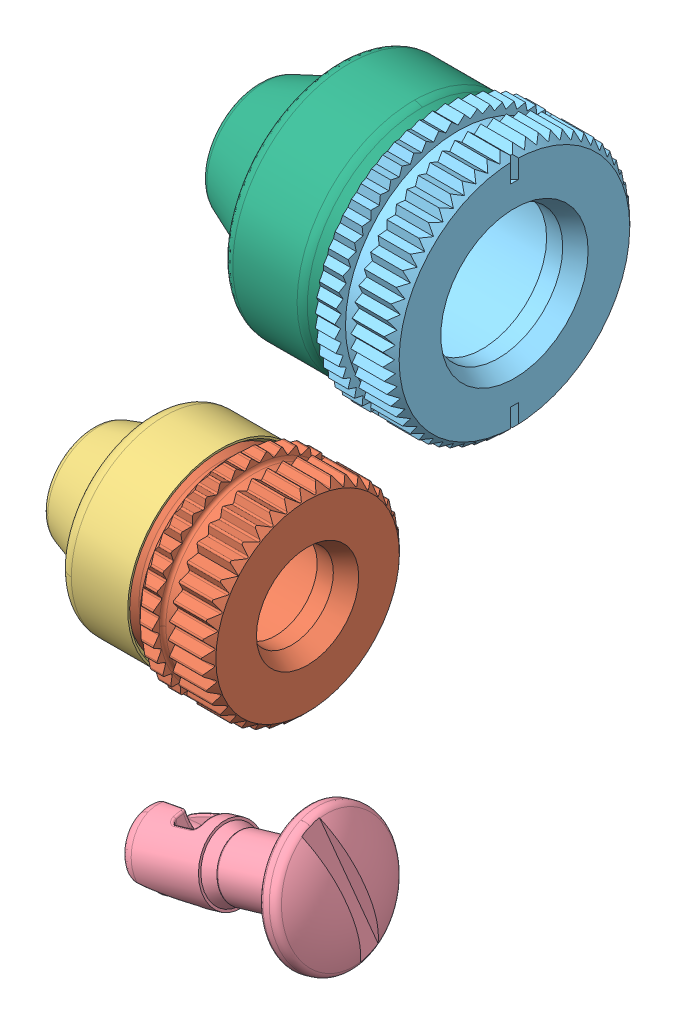
SolidWorks assembly Test_Twist_Lock_Assembly, configuration Default. Lengths in mm.
Overall size (31.23 29.99 38.65).
9 component instances, 7 part files, 0 mates.
Components (placement in the parent):
- Southco-D8-334-100-300-1: Southco-D8-334-100-300 [Default] at (-1.6933 5.3217 11.6315) size (13.4 12.29 12.29)
  - SW3dPS-D8-334-100-300_TAB PLATE-1: SW3dPS-D8-334-100-300_TAB PLATE [Default] at (3 0 0) x (0 -1 0) z (0 0 1) size (9.5 1.42 8)
  - SW3dPS-D8-334-100-300_D3_PANEX_Front_Mount_Insert_Body-1: SW3dPS-D8-334-100-300_D3_PANEX_Front_Mount_Insert_Body [Default] at (0.1 0 0) x (1 0 0) z (0 -1 0) size (9.3 12.29 12.29)
  - SW3dPS-D8-334-100-300_D3_PANEX_Insert_Cup-1: SW3dPS-D8-334-100-300_D3_PANEX_Insert_Cup [Default] at origin size (8 11.55 11.55)
- Southco-D8-314-108-170-1: Southco-D8-314-108-170 [Default] at (15.5941 -1.9595 20.5929) x (-0.115718 0.246142 -0.962301) z (-0.226211 0.93682 0.266827) size (12.22 13.03 8)
- Southco-D8-336-100-300-1: Southco-D8-336-100-300 [Default] at (-1.3893 7.0798 3.538) size (15.99 15.33 15.33)
  - SW3dPS-D8-336-100-300_D8-336-101-300-1: SW3dPS-D8-336-100-300_D8-336-101-300 [Default] at (10.75 6.7 -6.7039) size (10.5 15.33 15.33)
  - SW3dPS-D8-336-100-300_D8-336-114-190-ASSY-1: SW3dPS-D8-336-100-300_D8-336-114-190-ASSY [Default] at (0.2587 6.7 -6.7039) size (10.93 14.55 14.56)
  - SW3dPS-D8-336-100-300_D8-336-113-190-1: SW3dPS-D8-336-100-300_D8-336-113-190 [Default] at (1.2587 6.7 -6.7039) size (2.5 13.1 11)
